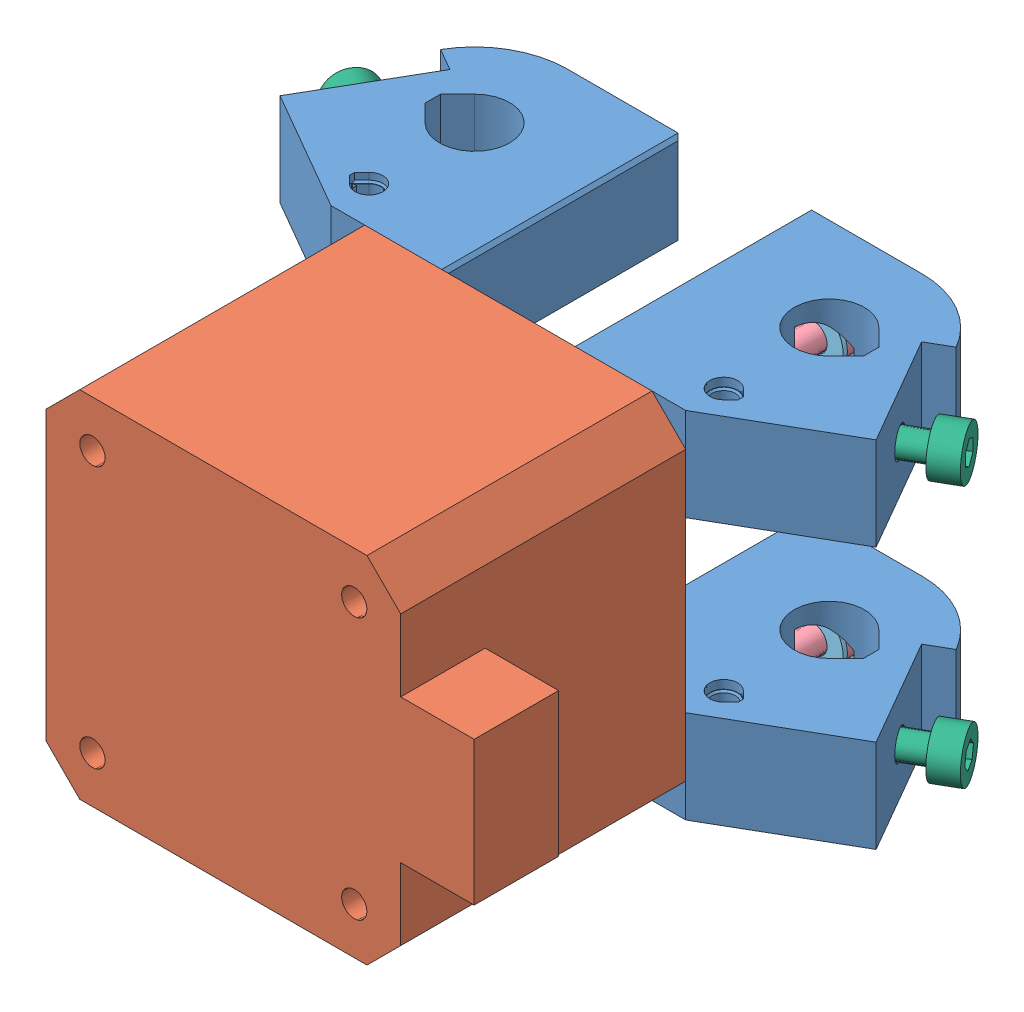
SolidWorks assembly motor-mount-assy, configuration Default. Lengths in mm.
Overall size (87.58 59.6 87.58).
19 component instances, 6 part files, 35 mates.
Components (placement in the parent):
- 1305-1: 1305 [Default] at (-40.5714 30.269 14.9676) size (27.79 11 28)
- motor-with-pulley-1: motor-with-pulley [Default] at (-8.9871 14.103 33.8237) x (-0.719549 -0.038441 0.693377) z (-0.693377 0.095039 -0.71428) size (78.14 49.22 80.4)
  - 408-1: 408 [Default] at (33.5099 6.4299 11.1332) x (0.719549 -0.038441 0.693377) z (-0.693377 -0.095039 0.71428) size (50.7 42 57.75)
  - 782-1: 782 [Default] at (1.3025 2.0154 44.3115) x (0.603928 0.464075 0.648001) z (0.693377 0.095039 -0.71428) size (14.7 14.7 14.3)
- 1305-2: 1305 [Default] at (-40.5714 -0.731 14.9676) size (27.79 11 28)
- 1305-3: 1305 [Default] at (-40.5714 10.269 14.9676) x (-1 0 0) z (0 0 1) size (27.79 11 28)
- 1305-4: 1305 [Default] at (-40.5714 41.269 14.9676) x (-1 0 0) z (0 0 1) size (27.79 11 28)
- 112-3: 112 [Default] at (-25.0714 4.769 -5.1687) x (0.866025 -0.5 0) z (0 0 -1) size (5.7 5.7 28)
- 112-2: 112 [Default] at (-25.0714 35.769 -5.1687) x (0.866025 -0.5 0) z (0 0 -1) size (5.7 5.7 28)
- 112-5: 112 [Default] at (-56.0714 35.769 -5.1687) x (0.866025 -0.5 0) z (0 0 -1) size (5.7 5.7 28)
- 112-4: 112 [Default] at (-56.0714 4.769 -5.1687) x (0.866025 -0.5 0) z (0 0 -1) size (5.7 5.7 28)
- 212-1: 212 [Default] at (-25.0714 4.769 -5.1687) x (0.866025 0.5 0) z (0 0 1) size (7 7 0.5)
- 212-2: 212 [Default] at (-56.0714 4.769 -5.1687) x (0.866025 0.5 0) z (0 0 1) size (7 7 0.5)
- 212-3: 212 [Default] at (-25.0714 35.769 -5.1687) x (0.866025 0.5 0) z (0 0 1) size (7 7 0.5)
- 212-4: 212 [Default] at (-56.0714 35.769 -5.1687) x (0.645481 0.763776 0) z (0 0 1) size (7 7 0.5)
- 242-1: 242 [Default] at (-74.5977 35.769 -0.4702) x (-0.096391 0.981242 0.166954) z (-0.866025 0 -0.5) size (5.7 5.7 19)
- 242-2: 242 [Default] at (-6.5451 35.769 -0.4702) x (-0.5 0 -0.866025) z (0.866025 0 -0.5) size (5.7 5.7 19)
- 242-3: 242 [Default] at (-74.5977 4.769 -0.4702) x (-0.5 0 0.866025) z (-0.866025 0 -0.5) size (5.7 5.7 19)
- 242-4: 242 [Default] at (-6.5451 4.769 -0.4702) x (-0.470872 -0.336328 -0.815575) z (0.866025 0 -0.5) size (5.7 5.7 19)
Mates (geometry in assembly coordinates):
- Coincident45: coincident anti-aligned: plane of 1305-1 through (-48.0714 41.269 15.9676) normal (0 0 1); plane of motor-with-pulley-1/408-1 through (-40.5714 20.269 15.9676) normal (0 0 -1)
- Concentric55: concentric anti-aligned: cylinder of 1305-1 through (-56.0714 35.769 -12.0324) axis (0 0 1) radius 1.65; cylinder of motor-with-pulley-1/408-1 through (-56.0714 35.769 20.9676) axis (0 0 -1) radius 1.5
- Coincident48: coincident anti-aligned: plane of motor-with-pulley-1/408-1 through (-40.5714 20.269 15.9676) normal (0 0 -1); plane of 1305-2 through (-48.0714 10.269 15.9676) normal (0 0 1)
- Concentric59: concentric anti-aligned: cylinder of motor-with-pulley-1/408-1 through (-56.0714 4.769 20.9676) axis (0 0 -1) radius 1.5; cylinder of 1305-2 through (-56.0714 4.769 -12.0324) axis (0 0 1) radius 1.65
- Coincident49: coincident anti-aligned: plane of motor-with-pulley-1/408-1 through (-40.5714 20.269 15.9676) normal (0 0 -1); plane of 1305-3 through (-33.0714 -0.731 15.9676) normal (0 0 1)
- Concentric61: concentric anti-aligned: cylinder of motor-with-pulley-1/408-1 through (-25.0714 4.769 20.9676) axis (0 0 -1) radius 1.5; cylinder of 1305-3 through (-25.0714 4.769 -12.0324) axis (0 0 1) radius 1.65
- Coincident50: coincident anti-aligned: plane of motor-with-pulley-1/408-1 through (-40.5714 20.269 15.9676) normal (0 0 -1); plane of 1305-4 through (-33.0714 30.269 15.9676) normal (0 0 1)
- Concentric63: concentric anti-aligned: cylinder of motor-with-pulley-1/408-1 through (-25.0714 35.769 20.9676) axis (0 0 -1) radius 1.5; cylinder of 1305-4 through (-25.0714 35.769 -12.0324) axis (0 0 1) radius 1.65
- Concentric258: concentric anti-aligned: cylinder of 1305-3 through (-25.0714 4.769 -12.0324) axis (0 0 1) radius 1.65; cylinder of 212-1 through (-25.0714 4.769 -4.6687) axis (0 0 -1) radius 1.6
- Concentric262: concentric aligned: cylinder of 212-1 through (-25.0714 4.769 -4.6687) axis (0 0 -1) radius 1.6; cylinder of 112-3 through (-25.0714 4.769 19.8313) axis (0 0 -1) radius 1.5
- Coincident200: coincident anti-aligned: plane of 212-1 through (-25.0714 4.769 -5.1687) normal (0 0 -1); plane of 112-3 through (-25.0714 4.769 -5.1687) normal (0 0 1)
- Concentric255: concentric anti-aligned: cylinder of 1305-2 through (-56.0714 4.769 -12.0324) axis (0 0 1) radius 1.65; cylinder of 212-2 through (-56.0714 4.769 -4.6687) axis (0 0 -1) radius 1.6
- Coincident203: coincident anti-aligned: plane of 212-2 through (-56.0714 4.769 -5.1687) normal (0 0 -1); plane of 112-4 through (-56.0714 4.769 -5.1687) normal (0 0 1)
- Concentric265: concentric aligned: cylinder of 212-2 through (-56.0714 4.769 -4.6687) axis (0 0 -1) radius 1.6; cylinder of 112-4 through (-56.0714 4.769 19.8313) axis (0 0 -1) radius 1.5
- Concentric261: concentric anti-aligned: cylinder of 1305-4 through (-25.0714 35.769 -12.0324) axis (0 0 1) radius 1.65; cylinder of 212-3 through (-25.0714 35.769 -4.6687) axis (0 0 -1) radius 1.6
- Coincident201: coincident anti-aligned: plane of 212-3 through (-25.0714 35.769 -5.1687) normal (0 0 -1); plane of 112-2 through (-25.0714 35.769 -5.1687) normal (0 0 1)
- Concentric263: concentric aligned: cylinder of 212-3 through (-25.0714 35.769 -4.6687) axis (0 0 -1) radius 1.6; cylinder of 112-2 through (-25.0714 35.769 19.8313) axis (0 0 -1) radius 1.5
- Concentric252: concentric anti-aligned: cylinder of 1305-1 through (-56.0714 35.769 -12.0324) axis (0 0 1) radius 1.65; cylinder of 212-4 through (-56.0714 35.769 -4.6687) axis (0 0 -1) radius 1.6
- Coincident202: coincident anti-aligned: plane of 212-4 through (-56.0714 35.769 -5.1687) normal (0 0 -1); plane of 112-5 through (-56.0714 35.769 -5.1687) normal (0 0 1)
- Concentric264: concentric aligned: cylinder of 212-4 through (-56.0714 35.769 -4.6687) axis (0 0 -1) radius 1.6; cylinder of 112-5 through (-56.0714 35.769 19.8313) axis (0 0 -1) radius 1.5
- Concentric266: concentric aligned: cylinder of 1305-1 through (-61.3752 35.769 9.0298) axis (-0.866025 0 -0.5) radius 1.4; cylinder of ? through (-63.6269 35.769 7.7298) axis (-0.866025 0 -0.5) radius 1.25
- Parallel1: parallel anti-aligned: plane of 1305-1 through (-63.6163 33.9813 10.9113) normal (0.5 0 -0.866025); plane of ? through (-65.0019 37.3567 10.1113) normal (-0.5 0 0.866025)
- Coincident204: coincident anti-aligned: plane of 1305-1 through (-63.5086 30.269 2.7248) normal (0.866025 0 0.5); plane of ? through (-65.7054 35.769 6.5298) normal (-0.866025 0 -0.5)
- Tangent1: tangent: cylinder of 1305-4 through (-19.5714 30.269 -1.0324) axis (0 1 0) radius 4.15; circle of 212-3
- Tangent2: tangent: cylinder of 1305-1 through (-61.5714 41.269 -1.0324) axis (0 -1 0) radius 4.15; circle of 212-4
- Tangent3: tangent: cylinder of 1305-3 through (-19.5714 -0.731 -1.0324) axis (0 1 0) radius 4.15; circle of 212-1
- Tangent4: tangent: cylinder of 1305-2 through (-61.5714 10.269 -1.0324) axis (0 -1 0) radius 4.15; circle of 212-2
- Concentric267: concentric aligned: cylinder of 1305-3 through (-16.9374 4.769 5.5298) axis (0.866025 0 -0.5) radius 1.7; cylinder of 242-4 through (-20.4015 4.769 7.5298) axis (0.866025 0 -0.5) radius 1.5
- Distance1: distance = 3 mm anti-aligned: plane of 242-4 through (-6.5451 4.769 -0.4702) normal (-0.866025 0 0.5); plane of 1305-3 through (-8.6432 -0.731 1.8958) normal (0.866025 0 -0.5)
- Concentric268: concentric aligned: cylinder of 1305-4 through (-16.9374 35.769 5.5298) axis (0.866025 0 -0.5) radius 1.7; cylinder of 242-2 through (-20.4015 35.769 7.5298) axis (0.866025 0 -0.5) radius 1.5
- Distance2: distance = 3 mm anti-aligned: plane of 242-2 through (-6.5451 35.769 -0.4702) normal (-0.866025 0 0.5); plane of 1305-4 through (-8.6432 30.269 1.8958) normal (0.866025 0 -0.5)
- Concentric269: concentric aligned: cylinder of 1305-2 through (-64.2054 4.769 5.5298) axis (-0.866025 0 -0.5) radius 1.7; cylinder of 242-3 through (-60.7413 4.769 7.5298) axis (-0.866025 0 -0.5) radius 1.5
- Distance3: distance = 3 mm anti-aligned: plane of 242-3 through (-74.5977 4.769 -0.4702) normal (0.866025 0 0.5); plane of 1305-2 through (-72.4996 10.269 1.8958) normal (-0.866025 0 -0.5)
- Concentric270: concentric aligned: cylinder of 1305-1 through (-64.2054 35.769 5.5298) axis (-0.866025 0 -0.5) radius 1.7; cylinder of 242-1 through (-60.7413 35.769 7.5298) axis (-0.866025 0 -0.5) radius 1.5
- Distance4: distance = 3 mm anti-aligned: plane of 242-1 through (-74.5977 35.769 -0.4702) normal (0.866025 0 0.5); plane of 1305-1 through (-72.4996 41.269 1.8958) normal (-0.866025 0 -0.5)
